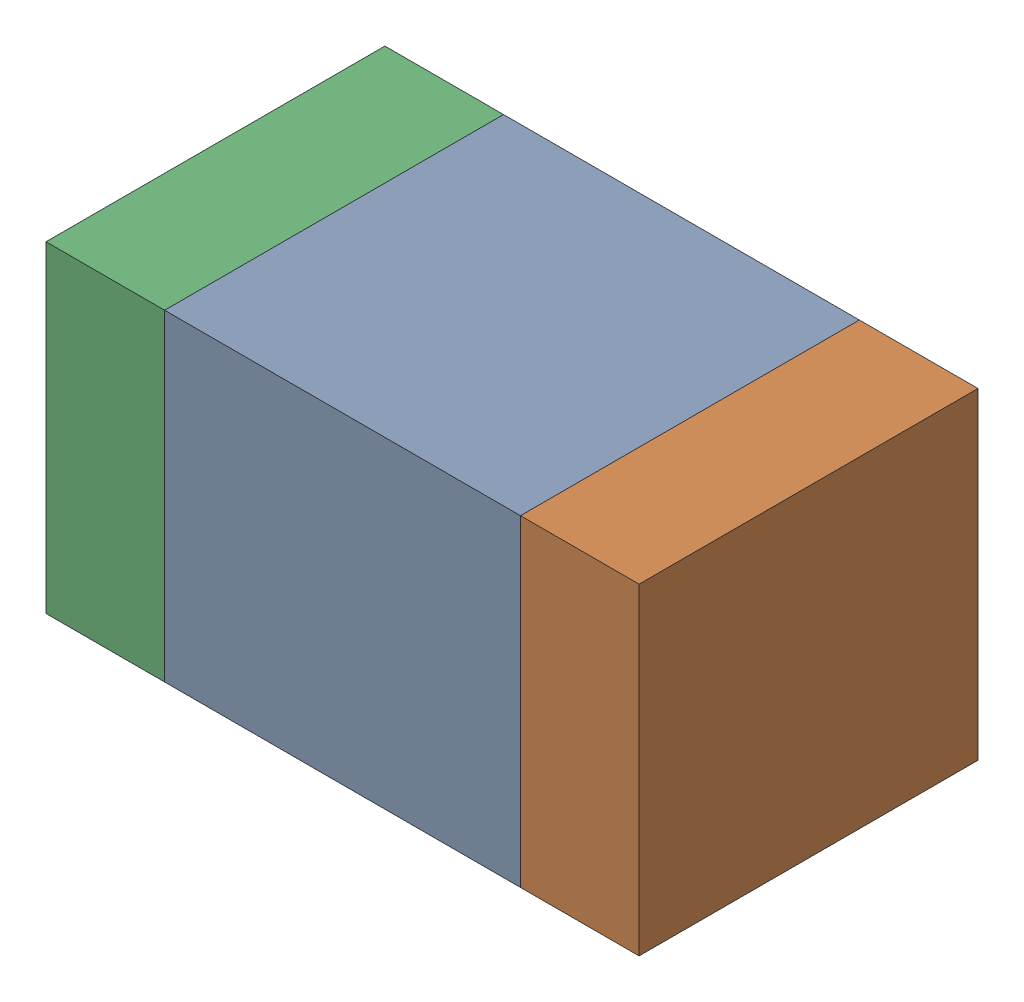
SolidWorks assembly C6, configuration Default. Lengths in mm.
Overall size (1.75 0.95 1).
6 component instances, 2 part files, 0 mates.
Components (placement in the parent):
- 959208800-1: 959208800 [Default] at (135.5285 81.379 0) size (1.05 0.95 1)
  - Extruded-17-1: Extruded-17 [Default] at origin size (1.05 0.95 1)
- 959208936-1: 959208936 [Default] at (136.2285 81.379 0) size (0.35 0.95 1)
  - Extruded-16-1: Extruded-16 [Default] at origin size (0.35 0.95 1)
- 959208936-2: 959208936 [Default] at (134.8286 81.379 0) size (0.35 0.95 1)
  - Extruded-16-1: Extruded-16 [Default] at origin size (0.35 0.95 1)
